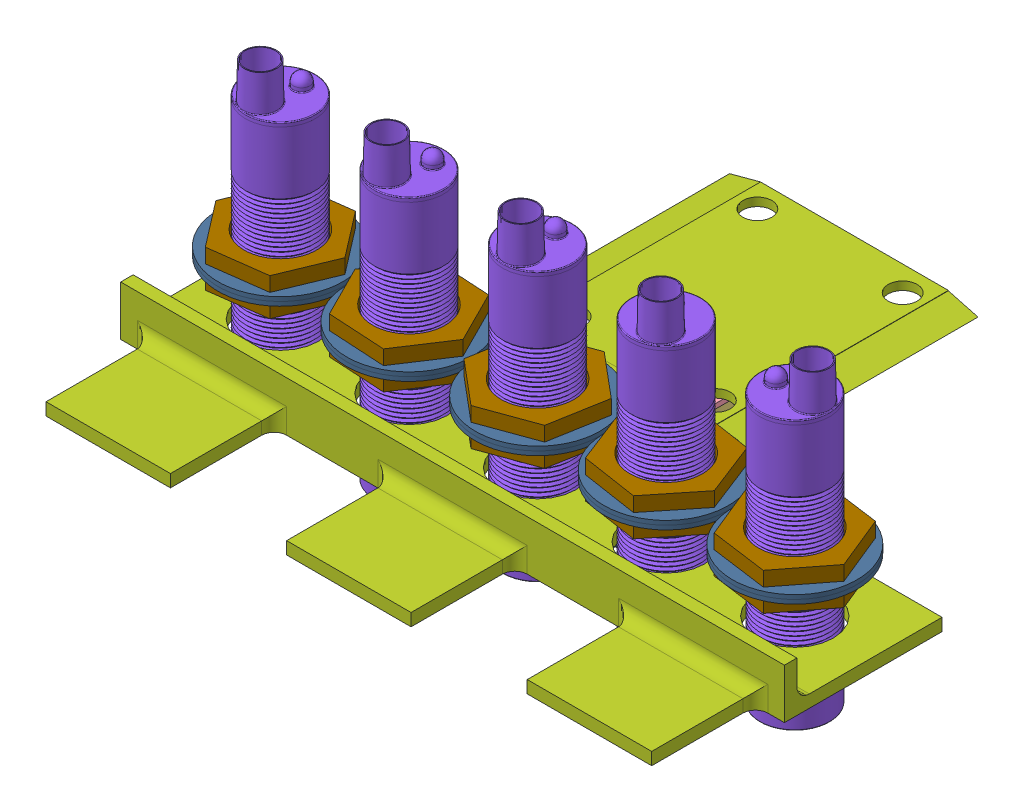
SolidWorks assembly Assem1, configuration Default. Lengths in mm.
Overall size (164.68 85.93 122).
38 component instances, 10 part files, 14 mates.
Components (placement in the parent):
- CasterWheel.stp-1: CasterWheel.stp [Default] at (16.4254 17.7176 46.1173) size (32.15 38.14 46.59)
  - CasterWheel1.stp-1: CasterWheel1.stp [Default] x (-1 0 0) z (0 1 0) size (15.8 31.03 31.03)
  - WheelAxle.stp-1: WheelAxle.stp [Default] x (-1 0 0) z (0 1 0) size (22.8 8.6 8.6)
  - MainCasterBody.stp-1: MainCasterBody.stp [Default] x (0 1 0) z (1 0 0) size (24.81 29.01 25)
  - UpperCasterBody.stp-1: UpperCasterBody.stp [Default] at (1.7235 22.6224 -13.5277) size (32.15 1.89 38.15)
  - Bearings.stp-1: Bearings.stp [Default] x (0 1 0) z (1 0 0) size (2.12 15.93 15.93)
  - CasterShaft.stp-1: CasterShaft.stp [Default] x (0 -1 0) z (1 0 0) size (5.13 8 8)
- Part7^Assem1-1: Part7^Assem1 [Default] at origin size (160 13 122)
- Inductive Proximity Sensor-1: Inductive Proximity Sensor [Default] at (-0.3813 72.914 140.2406) x (0 -1 0) z (0.384361 0 -0.923183) size (73.6 36.66 36.27)
  - Sensor Body-1: Sensor Body [Default] at (-6.2225 39.7633 58.5792) size (73.6 17.21 17.21)
  - Nut-1: Nut [Default] at (25.4974 39.7633 58.5792) x (0 0.757948 0.652315) z (0 -0.652315 0.757948) size (27.71 3.5 24)
  - Nut-2: Nut [Default] at (30.9974 39.7633 58.5792) x (0 0.757948 0.652315) z (0 -0.652315 0.757948) size (27.71 3.5 24)
  - Washer-1: Washer [Default] at (26.4974 39.7633 58.5792) x (0 0 -1) z (0 1 0) size (30 1 30)
  - Washer-2: Washer [Default] at (27.4974 39.7633 58.5792) x (0 0 -1) z (0 1 0) size (30 1 30)
- Inductive Proximity Sensor-2: Inductive Proximity Sensor [Default] at (-18.5639 73.114 136.3229) x (0 -1 0) z (0.203496 0 -0.979076) size (73.6 36.66 36.27)
  - Sensor Body-1: Sensor Body [Default] at (-6.2225 39.7633 58.5792) size (73.6 17.21 17.21)
  - Nut-1: Nut [Default] at (25.4974 39.7633 58.5792) x (0 0.757948 0.652315) z (0 -0.652315 0.757948) size (27.71 3.5 24)
  - Nut-2: Nut [Default] at (30.9974 39.7633 58.5792) x (0 0.757948 0.652315) z (0 -0.652315 0.757948) size (27.71 3.5 24)
  - Washer-1: Washer [Default] at (26.4974 39.7633 58.5792) x (0 0 -1) z (0 1 0) size (30 1 30)
  - Washer-2: Washer [Default] at (27.4974 39.7633 58.5792) x (0 0 -1) z (0 1 0) size (30 1 30)
- Inductive Proximity Sensor-5: Inductive Proximity Sensor [Default] at (56.9093 72.914 128.9614) x (0 -1 0) z (-0.012351 0 -0.999924) size (73.6 36.66 36.27)
  - Sensor Body-1: Sensor Body [Default] at (-6.2225 39.7633 58.5792) size (73.6 17.21 17.21)
  - Nut-1: Nut [Default] at (25.4974 39.7633 58.5792) x (0 0.757948 0.652315) z (0 -0.652315 0.757948) size (27.71 3.5 24)
  - Nut-2: Nut [Default] at (30.9974 39.7633 58.5792) x (0 0.757948 0.652315) z (0 -0.652315 0.757948) size (27.71 3.5 24)
  - Washer-1: Washer [Default] at (26.4974 39.7633 58.5792) x (0 0 -1) z (0 1 0) size (30 1 30)
  - Washer-2: Washer [Default] at (27.4974 39.7633 58.5792) x (0 0 -1) z (0 1 0) size (30 1 30)
- Inductive Proximity Sensor-7: Inductive Proximity Sensor [Default] at (112.1781 72.914 99.509) x (0 -1 0) z (-0.529597 0 -0.848249) size (73.6 36.66 36.27)
  - Sensor Body-1: Sensor Body [Default] at (-6.2225 39.7633 58.5792) size (73.6 17.21 17.21)
  - Nut-1: Nut [Default] at (25.4974 39.7633 58.5792) x (0 0.757948 0.652315) z (0 -0.652315 0.757948) size (27.71 3.5 24)
  - Nut-2: Nut [Default] at (30.9974 39.7633 58.5792) x (0 0.757948 0.652315) z (0 -0.652315 0.757948) size (27.71 3.5 24)
  - Washer-1: Washer [Default] at (26.4974 39.7633 58.5792) x (0 0 -1) z (0 1 0) size (30 1 30)
  - Washer-2: Washer [Default] at (27.4974 39.7633 58.5792) x (0 0 -1) z (0 1 0) size (30 1 30)
- Inductive Proximity Sensor-9: Inductive Proximity Sensor [Default] at (134.9131 72.914 28.1952) x (0 -1 0) z (-0.998714 0 0.050707) size (73.6 36.66 36.27)
  - Sensor Body-1: Sensor Body [Default] at (-6.2225 39.7633 58.5792) size (73.6 17.21 17.21)
  - Nut-1: Nut [Default] at (25.4974 39.7633 58.5792) x (0 0.757948 0.652315) z (0 -0.652315 0.757948) size (27.71 3.5 24)
  - Nut-2: Nut [Default] at (30.9974 39.7633 58.5792) x (0 0.757948 0.652315) z (0 -0.652315 0.757948) size (27.71 3.5 24)
  - Washer-1: Washer [Default] at (26.4974 39.7633 58.5792) x (0 0 -1) z (0 1 0) size (30 1 30)
  - Washer-2: Washer [Default] at (27.4974 39.7633 58.5792) x (0 0 -1) z (0 1 0) size (30 1 30)
Mates (geometry in assembly coordinates):
- Parallel1: parallel aligned: plane of Part7^Assem1-1 through (0 29.34 0) normal (0 -1 0); plane of Inductive Proximity Sensor-1/Sensor Body-1 through (-14.5746 14.3365 70.8777) normal (0 -1 0)
- Parallel2: parallel aligned: plane of Part7^Assem1-1 through (0 29.34 0) normal (0 -1 0); plane of Inductive Proximity Sensor-2/Sensor Body-1 through (-45.5746 14.5365 70.8777) normal (0 -1 0)
- Parallel4: parallel aligned: plane of Part7^Assem1-1 through (0 29.34 0) normal (0 -1 0); plane of Inductive Proximity Sensor-5/Sensor Body-1 through (16.4254 14.3365 70.8777) normal (0 -1 0)
- Parallel5: parallel aligned: plane of Part7^Assem1-1 through (0 29.34 0) normal (0 -1 0); plane of Inductive Proximity Sensor-7/Sensor Body-1 through (47.4254 14.3365 70.8777) normal (0 -1 0)
- Parallel6: parallel aligned: plane of Part7^Assem1-1 through (0 29.34 0) normal (0 -1 0); plane of Inductive Proximity Sensor-9/Sensor Body-1 through (78.4254 14.3365 70.8777) normal (0 -1 0)
- Coincident2: coincident aligned: plane of Inductive Proximity Sensor-7/Sensor Body-1 through (47.4254 14.3365 70.8777) normal (0 -1 0); plane of Inductive Proximity Sensor-9/Sensor Body-1 through (78.4254 14.3365 70.8777) normal (0 -1 0)
- Coincident3: coincident aligned: plane of Inductive Proximity Sensor-5/Sensor Body-1 through (16.4254 14.3365 70.8777) normal (0 -1 0); plane of Inductive Proximity Sensor-7/Sensor Body-1 through (47.4254 14.3365 70.8777) normal (0 -1 0)
- Coincident4: coincident anti-aligned: plane of Inductive Proximity Sensor-2/Sensor Body-1 through (-45.5746 14.5365 70.8777) normal (0 -1 0); circle of Inductive Proximity Sensor-5/Sensor Body-1
- Coincident5: coincident aligned: plane of Inductive Proximity Sensor-1/Sensor Body-1 through (-14.5746 14.3365 70.8777) normal (0 -1 0); plane of Inductive Proximity Sensor-7/Sensor Body-1 through (47.4254 14.3365 70.8777) normal (0 -1 0)
- Concentric6: concentric aligned: circle of Part7^Assem1-1; circle of Inductive Proximity Sensor-2/Sensor Body-1
- Concentric7: concentric aligned: circle of Part7^Assem1-1; circle of Inductive Proximity Sensor-1/Sensor Body-1
- Concentric8: concentric aligned: circle of Part7^Assem1-1; circle of Inductive Proximity Sensor-5/Sensor Body-1
- Concentric9: concentric aligned: circle of Part7^Assem1-1; circle of Inductive Proximity Sensor-7/Sensor Body-1
- Concentric10: concentric aligned: circle of Part7^Assem1-1; circle of Inductive Proximity Sensor-9/Sensor Body-1
